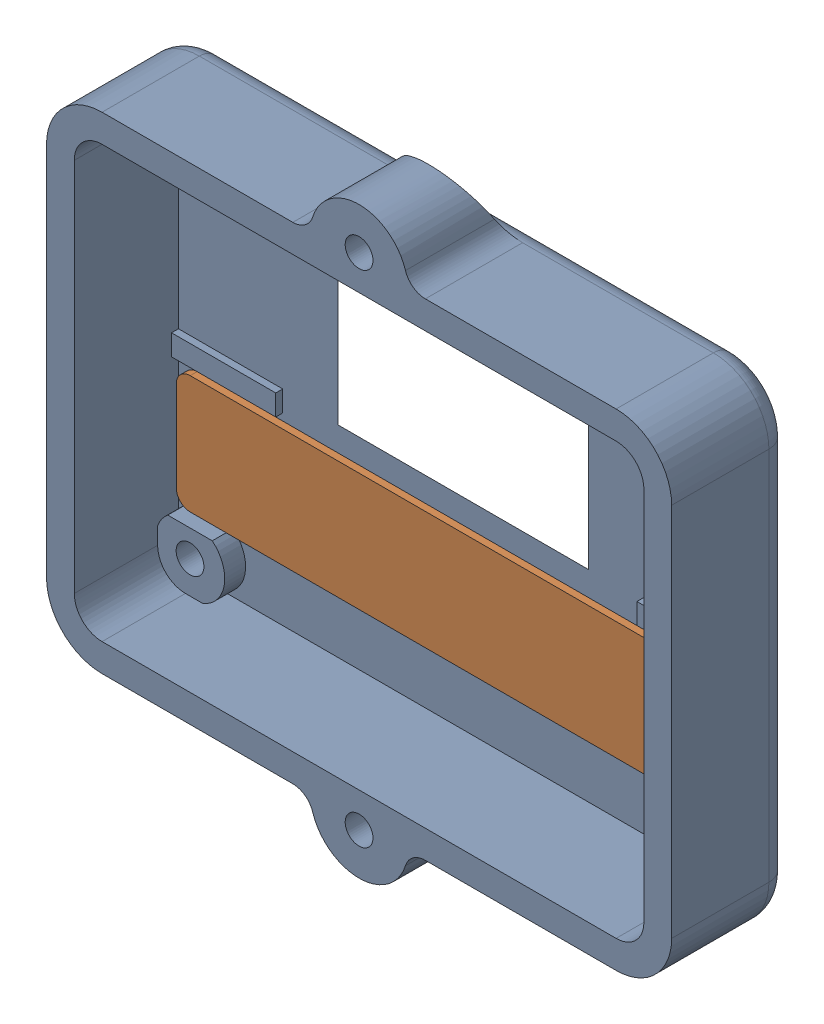
SolidWorks assembly Assem1, configuration Default. Lengths in mm.
Overall size (90 84 17).
2 component instances, 2 part files, 2 mates.
Components (placement in the parent):
- uibox-1: uibox [Default] at origin size (90 84 17)
- defuser-1: defuser [Default] at (0.1867 -14 2) size (81 17 1)
Mates (geometry in assembly coordinates):
- Coincident1: coincident anti-aligned: plane of uibox-1 through (0 0 2) normal (0 0 1); plane of defuser-1 through (38.6867 -7.5 2) normal (0 0 -1)
- Coincident2: coincident anti-aligned: plane of uibox-1 through (-41 -22.5 2) normal (0 1 0); plane of defuser-1 through (-38.3133 -22.5 3) normal (0 -1 0)
